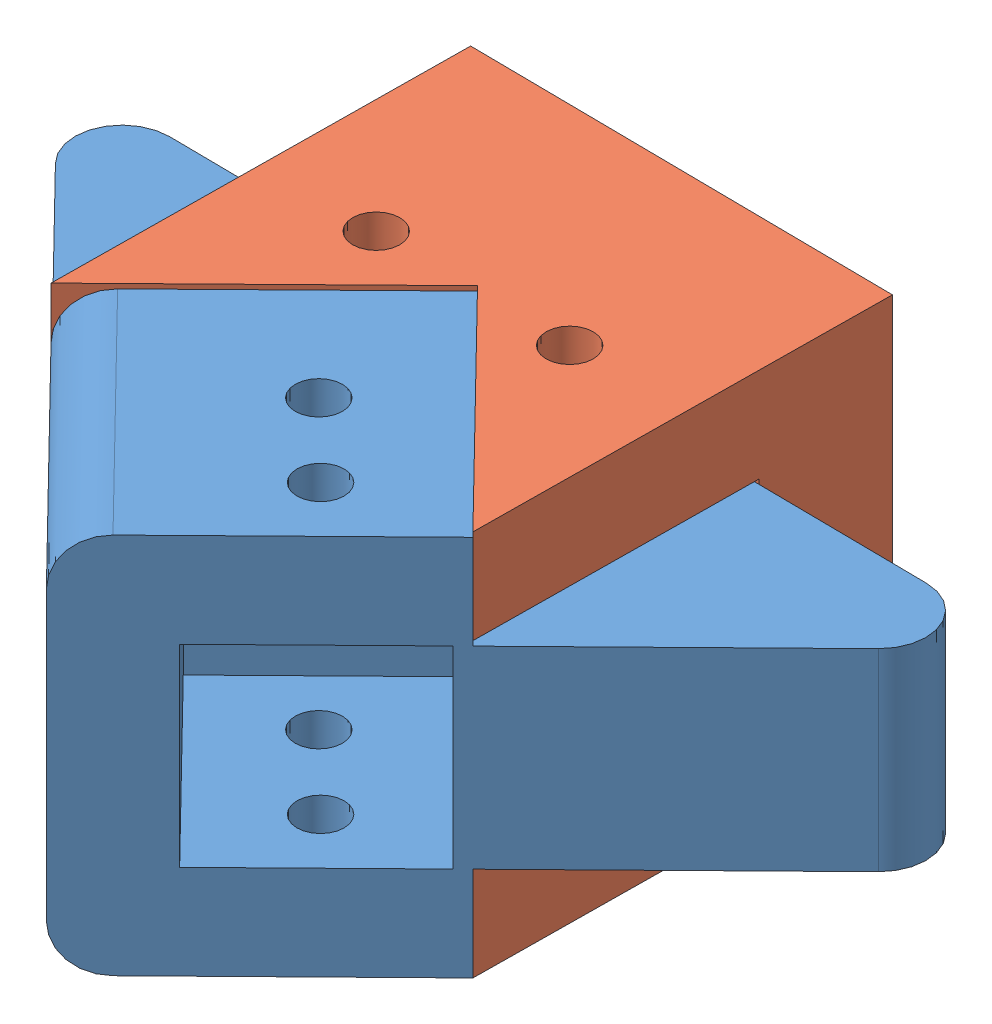
SolidWorks assembly dasdasdsadsa, configuration Default. Lengths in mm.
Overall size (95.35 41 95.35).
2 component instances, 2 part files, 6 mates.
Components (placement in the parent):
- motortutucuon_ters-1: motortutucuon_ters [Varsayılan] at (-2.9814 5.5652 73.4929) x (-0.714756 0 0.699374) z (0 1 0) size (67.43 67.43 40.5)
- motorarkaturucu-1: motorarkaturucu [Varsayılan] at (13.8101 5.5627 52.6902) x (-0.999942 0 -0.010769) z (0.010769 0 -0.999942) size (45.25 41 44.05)
Mates (geometry in assembly coordinates):
- Coincident9: coincident: plane of motortutucuarka-1 through (-27.5455 5.5652 46.4864) normal (0 1 0); plane of motortutucuon_ters-1 through (-2.9814 5.5652 73.4929) normal (0 -1 0)
- Coincident10: coincident: plane of motortutucuarka-1 through (-27.8932 -4.4348 78.4595) normal (0.699374 0 0.714756); plane of motortutucuon_ters-1 through (-31.769 -2.4348 82.2518) normal (-0.699374 0 -0.714756)
- Coincident11: coincident anti-aligned: plane of motortutucuarka-1 through (-8.8968 -4.4348 59.8718) normal (-0.714756 0 0.699374); plane of motortutucuon_ters-1 through (-8.8968 -2.4348 59.8718) normal (0.714756 0 -0.699374)
- Concentric1: concentric aligned: cylinder of motortutucuon_ters-1 through (-19.2762 -13.9348 60.2343) axis (0 1 0) radius 2.5; cylinder of motorarkaturucu-1 through (-19.2762 -8.4373 60.2343) axis (0 1 0) radius 2.5
- Parallel2: parallel anti-aligned: plane of motortutucuon_ters-1 through (13.4832 33.0652 82.744) normal (0.714756 0 -0.699374); plane of motorarkaturucu-1 through (13.4865 36.5627 82.7385) normal (-0.714756 0 0.699374)
- Parallel3: parallel anti-aligned: line of motortutucuon_ters-1 through (13.4832 36.0652 82.744) axis (-0.699374 0 -0.714756); line of motorarkaturucu-1 through (-8.8935 36.5627 59.8663) axis (0.699374 0 0.714756)
